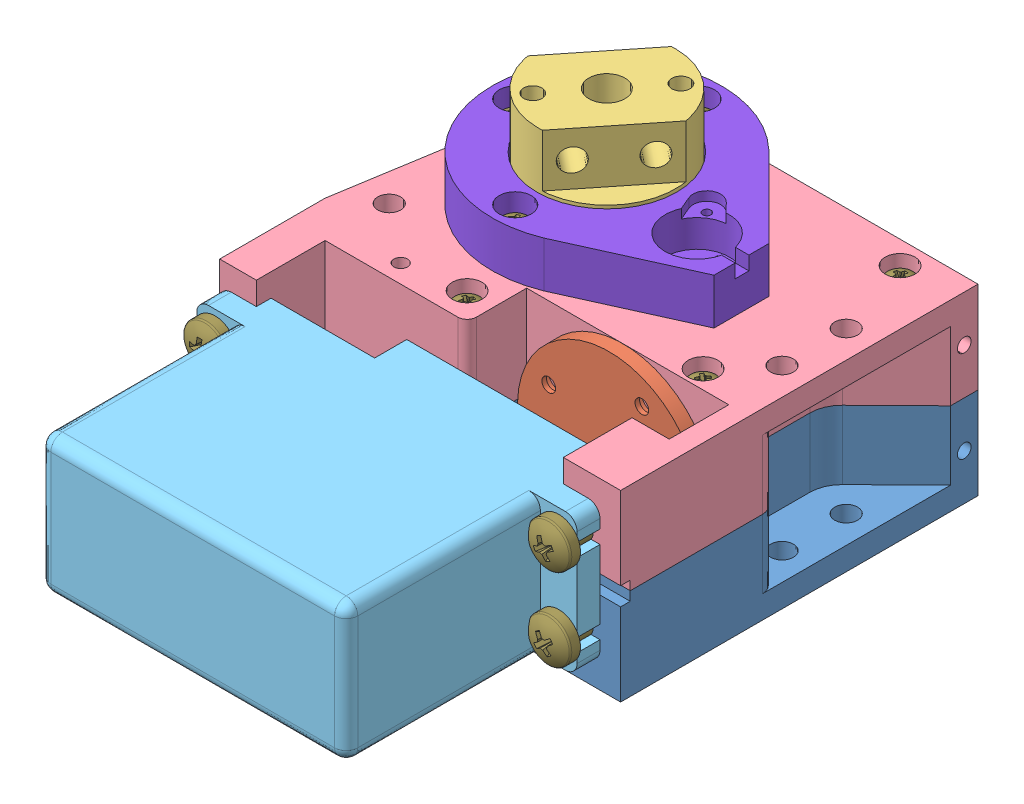
SolidWorks assembly Mirrorgearbox1, configuration Default. Lengths in mm.
Overall size (90.22 74 134.56).
28 component instances, 12 part files, 58 mates.
Components (placement in the parent):
- Mirrorservo gearbox-1: Mirrorservo gearbox [Default] at (7.4002 -24.2748 -89.7718) x (1 0 0) z (0 -1 0) size (87.5 78 20)
- wormscrew-1: wormscrew [Default] at (21.4002 -4.2748 -75.7718) x (-0.47589 -0.879505 0) z (0 0 -1) size (40 40 51)
- driveshaft cog-1: driveshaft cog [Default] at (-6.5998 -9.2748 -103.2718) x (0.623441 0 -0.78187) z (0 1 0) size (49.29 49.31 47)
- Mirrorgearbox top-1: Mirrorgearbox top [Default] at (-6.5998 15.7252 -103.2718) x (-1 0 0) z (0 1 0) size (87.5 78 40)
- HS-805BB-1: HS-805BB [Default] at (2.9002 -19.2748 -28.6693) x (1 0 0) z (0 1 0) size (83 68.8 30)
- 608ZZ-1: 608ZZ [Default] at (21.4002 -4.2748 -127.5718) x (0.996867 0.079098 0) z (0 0 1) size (22 22 7)
- 6806 30x42x7-1: 6806 30x42x7 [Default] at (-6.5998 -22.2748 -103.2718) x (0.979879 0 -0.199591) z (0 1 0) size (42 42 7)
- 6806 30x42x7-2: 6806 30x42x7 [Default] at (-6.5998 9.7252 -103.2718) x (0.968497 0 -0.249026) z (0 -1 0) size (42 42 7)
- Mirrorbottom plate pot holder-1: Mirrorbottom plate pot holder [Default] at (-6.5998 15.7252 -103.2718) x (0 0 1) z (0 -1 0) size (50 60 10)
- cog brace-1: cog brace [Default] at (18.6002 9.7252 -104.6718) x (1 0 0) z (0 -1 0) size (8.5 22.65 3)
- pot cog-1: pot cog [Default] at (18.6002 12.7252 -97.7718) x (0.51355 0 -0.85806) z (0 -1 0) size (28 27.88 7.9)
- driveshaft-1: driveshaft [Default] at (-6.5998 -9.2748 -103.2718) x (-0.623441 0 0.78187) z (0 -1 0) size (36.44 35.48 27)
- Pan Head Cross Recess Screw_ISO-1: Pan Head Cross Recess Screw_ISO [ISO 7045 - M3 x 10 - Z --- 10N] at (-26.5998 23.1252 -103.2718) x (0 -1 0) z (0 0 -1) size (12.35 5.6 5.6)
- Pan Head Cross Recess Screw_ISO-2: Pan Head Cross Recess Screw_ISO [ISO 7045 - M3 x 10 - Z --- 10N] at (-6.5998 23.1252 -123.2718) x (0 -1 0) z (0.495758 0 -0.868461) size (12.35 5.6 5.6)
- Pan Head Cross Recess Screw_ISO-3: Pan Head Cross Recess Screw_ISO [ISO 7045 - M3 x 10 - Z --- 10N] at (-6.5998 23.1252 -83.2718) x (0 -1 0) z (0.927545 0 -0.373711) size (12.35 5.6 5.6)
- Pan Head Cross Recess Screw_ISO-4: Pan Head Cross Recess Screw_ISO [ISO 7045 - M5 x 12 - Z --- 12N] at (-34.5998 -13.2748 -42.0718) x (0 0 -1) z (-1 0 0) size (15.63 9.5 9.5)
- Pan Head Cross Recess Screw_ISO-5: Pan Head Cross Recess Screw_ISO [ISO 7045 - M5 x 12 - Z --- 12N] at (-34.5998 4.7252 -42.0718) x (0 0 -1) z (-1 0 0) size (15.63 9.5 9.5)
- Pan Head Cross Recess Screw_ISO-6: Pan Head Cross Recess Screw_ISO [ISO 7045 - M3 x 30 - Z --- 25N] at (-27.0895 14.1252 -123.7718) x (0 -1 0) z (0 0 -1) size (32.35 5.6 5.6)
- Pan Head Cross Recess Screw_ISO-7: Pan Head Cross Recess Screw_ISO [ISO 7045 - M3 x 30 - Z --- 25N] at (-18.0998 -22.6748 -69.7718) x (0 1 0) z (0 0 -1) size (32.35 5.6 5.6)
- Pan Head Cross Recess Screw_ISO-8: Pan Head Cross Recess Screw_ISO [ISO 7045 - M3 x 30 - Z --- 25N] at (34.9002 14.1252 -82.7718) x (0 -1 0) z (-0.8218 0 -0.569776) size (32.35 5.6 5.6)
- Pan Head Cross Recess Screw_ISO-9: Pan Head Cross Recess Screw_ISO [ISO 7045 - M3 x 30 - Z --- 25N] at (-5.5998 14.1252 -71.7718) x (0 -1 0) z (0.38373 0 -0.923445) size (32.35 5.6 5.6)
- Pan Head Cross Recess Screw_ISO-10: Pan Head Cross Recess Screw_ISO [ISO 7045 - M2 x 6 - Z --- 6N] at (18.6002 6.6252 -115.2718) x (0 1 0) z (0.855583 0 0.517665) size (7.57 4 4)
- Pan Head Cross Recess Screw_ISO-11: Pan Head Cross Recess Screw_ISO [ISO 7045 - M3 x 5 - Z --- 5N] at (-19.8916 -13.6748 -113.8703) x (0 1 0) z (0.934817 0 -0.355129) size (7.35 5.6 5.6)
- Pan Head Cross Recess Screw_ISO-12: Pan Head Cross Recess Screw_ISO [ISO 7045 - M3 x 5 - Z --- 5N] at (9.2246 -13.6748 -109.4836) x (0 1 0) z (-0.000145 0 -1) size (7.35 5.6 5.6)
- Pan Head Cross Recess Screw_ISO-13: Pan Head Cross Recess Screw_ISO [ISO 7045 - M3 x 5 - Z --- 5N] at (-9.1325 -13.6748 -86.4615) x (0 1 0) z (-0.12044 0 -0.992721) size (7.35 5.6 5.6)
- Pan Head Cross Recess Screw_ISO-14: Pan Head Cross Recess Screw_ISO [ISO 7045 - M3 x 30 - Z --- 25N] at (36.9002 14.1252 -123.7718) x (0 -1 0) z (0.993717 0 0.111922) size (32.35 5.6 5.6)
- Pan Head Cross Recess Screw_ISO-15: Pan Head Cross Recess Screw_ISO [ISO 7045 - M5 x 12 - Z --- 12N] at (40.4002 4.7252 -42.0718) x (0 0 -1) z (0.445798 -0.895134 0) size (15.63 9.5 9.5)
- Pan Head Cross Recess Screw_ISO-16: Pan Head Cross Recess Screw_ISO [ISO 7045 - M5 x 12 - Z --- 12N] at (40.4002 -13.2748 -42.0718) x (0 0 -1) z (0.583619 -0.812027 0) size (15.63 9.5 9.5)
Mates (geometry in assembly coordinates):
- Coincident1: coincident anti-aligned: plane of Mirrorservo gearbox-1 through (-34.0998 -4.2748 -50.7718) normal (0 0 1); plane of HS-805BB-1 through (-38.5998 10.7252 -50.7718) normal (0 0 -1)
- Concentric1: concentric aligned: circle of wormscrew-1; circle of HS-805BB-1
- Coincident2: coincident anti-aligned: plane of Mirrorservo gearbox-1 through (36.4002 11.2494 -65.7718) normal (-1 0 0); plane of HS-805BB-1 through (36.4002 10.7252 -50.7718) normal (1 0 0)
- Coincident3: coincident anti-aligned: plane of Mirrorservo gearbox-1 through (32.6502 -15.4748 -127.5718) normal (0 0 1); plane of 608ZZ-1 through (21.4002 -4.2748 -127.5718) normal (0 0 -1)
- Coincident4: coincident anti-aligned: plane of Mirrorservo gearbox-1 through (-6.5998 -22.2748 -103.2718) normal (0 1 0); plane of 6806 30x42x7-1 through (-6.5998 -22.2748 -103.2718) normal (0 -1 0)
- Concentric2: concentric anti-aligned: cylinder of Mirrorservo gearbox-1; cylinder of 6806 30x42x7-1
- Coincident5: coincident anti-aligned: plane of driveshaft cog-1 through (-6.5998 2.7252 -103.2718) normal (0 1 0); plane of 6806 30x42x7-2 through (-6.5998 2.7252 -103.2718) normal (0 -1 0)
- Concentric4: concentric anti-aligned: cylinder of HS-805BB-1; cylinder of Pan Head Cross Recess Screw_ISO-15
- Coincident6: coincident anti-aligned: plane of HS-805BB-1 through (36.4002 10.7252 -45.7718) normal (0 0 1); plane of Pan Head Cross Recess Screw_ISO-15 through (42.638 5.8397 -45.7718) normal (0 0 -1)
- Concentric5: concentric anti-aligned: cylinder of HS-805BB-1; cylinder of Pan Head Cross Recess Screw_ISO-16
- Coincident7: coincident anti-aligned: plane of HS-805BB-1 through (36.4002 10.7252 -45.7718) normal (0 0 1); plane of Pan Head Cross Recess Screw_ISO-16 through (42.4302 -11.8157 -45.7718) normal (0 0 -1)
- Concentric6: concentric anti-aligned: cylinder of HS-805BB-1; cylinder of Pan Head Cross Recess Screw_ISO-4
- Coincident8: coincident anti-aligned: plane of HS-805BB-1 through (-30.5998 10.7252 -45.7718) normal (0 0 1); plane of Pan Head Cross Recess Screw_ISO-4 through (-34.5998 -15.7748 -45.7718) normal (0 0 -1)
- Concentric7: concentric anti-aligned: cylinder of HS-805BB-1; cylinder of Pan Head Cross Recess Screw_ISO-5
- Coincident9: coincident anti-aligned: plane of HS-805BB-1 through (-30.5998 10.7252 -45.7718) normal (0 0 1); plane of Pan Head Cross Recess Screw_ISO-5 through (-34.5998 2.2252 -45.7718) normal (0 0 -1)
- Coincident10: coincident anti-aligned: plane of Mirrorservo gearbox-1 through (-18.0998 -20.2748 -69.7718) normal (0 -1 0); plane of Pan Head Cross Recess Screw_ISO-7 through (-16.5998 -20.2748 -69.7718) normal (0 1 0)
- Coincident11: coincident anti-aligned: plane of cog brace-1 through (23.1002 8.2252 -111.6718) normal (0 -1 0); plane of Pan Head Cross Recess Screw_ISO-10 through (18.0825 8.2252 -114.4162) normal (0 1 0)
- Concentric8: concentric aligned: cylinder of driveshaft cog-1; cylinder of Pan Head Cross Recess Screw_ISO-11
- Concentric9: concentric anti-aligned: cylinder of Mirrorbottom plate pot holder-1; cylinder of Pan Head Cross Recess Screw_ISO-2
- Coincident12: coincident anti-aligned: plane of Mirrorbottom plate pot holder-1 through (-6.5998 20.7252 -123.2718) normal (0 1 0); plane of Pan Head Cross Recess Screw_ISO-2 through (-7.9025 20.7252 -124.0154) normal (0 -1 0)
- Concentric10: concentric anti-aligned: cylinder of Mirrorbottom plate pot holder-1; cylinder of Pan Head Cross Recess Screw_ISO-3
- Coincident13: coincident anti-aligned: plane of Mirrorbottom plate pot holder-1 through (-6.5998 20.7252 -83.2718) normal (0 1 0); plane of Pan Head Cross Recess Screw_ISO-3 through (-7.1604 20.7252 -84.6631) normal (0 -1 0)
- Coincident14: coincident anti-aligned: plane of Mirrorbottom plate pot holder-1 through (-26.5998 20.7252 -103.2718) normal (0 1 0); plane of Pan Head Cross Recess Screw_ISO-1 through (-28.0998 20.7252 -103.2718) normal (0 -1 0)
- Concentric11: concentric anti-aligned: cylinder of Mirrorbottom plate pot holder-1; cylinder of Pan Head Cross Recess Screw_ISO-1
- GearMate1: gear = 0.001 : 0.013: circle of driveshaft cog-1; circle of wormscrew-1
- GearMate2: gear = 0.001 : 0.001: circle of pot cog-1; circle of driveshaft cog-1
- Coincident16: coincident aligned: plane of Mirrorgearbox top-1 through (-6.5998 9.7252 -103.2718) normal (0 -1 0); circle of 6806 30x42x7-2
- Concentric13: concentric anti-aligned: cylinder of Mirrorgearbox top-1; cylinder of 6806 30x42x7-2
- Concentric14: concentric anti-aligned: cylinder of driveshaft cog-1; cylinder of Mirrorgearbox top-1
- Coincident17: coincident anti-aligned: plane of Mirrorgearbox top-1 through (18.6002 12.7252 -97.7718) normal (0 -1 0); plane of pot cog-1 through (20.5571 12.7252 -91.7908) normal (0 1 0)
- Concentric16: concentric aligned: circle of cog brace-1; cylinder of Pan Head Cross Recess Screw_ISO-10
- Concentric17: concentric aligned: cylinder of Mirrorgearbox top-1; cylinder of Pan Head Cross Recess Screw_ISO-10
- Coincident19: coincident anti-aligned: plane of Mirrorgearbox top-1 through (23.1002 9.7252 -108.9666) normal (0 -1 0); plane of cog brace-1 through (20.8502 9.7252 -97.6718) normal (0 1 0)
- Concentric19: concentric anti-aligned: circle of driveshaft cog-1; circle of driveshaft-1
- Coincident22: coincident aligned: cylinder of driveshaft cog-1; circle of driveshaft-1
- Coincident23: coincident anti-aligned: plane of Pan Head Cross Recess Screw_ISO-11 through (-19.3589 -11.2748 -112.4681) normal (0 1 0); plane of driveshaft-1 through (-19.8916 -11.2748 -113.8703) normal (0 -1 0)
- Coincident24: coincident anti-aligned: plane of driveshaft cog-1 through (-6.5998 -9.2748 -103.2718) normal (0 -1 0); plane of driveshaft-1 through (-6.5998 -9.2748 -103.2718) normal (0 1 0)
- Coincident25: coincident aligned: circle of driveshaft-1; cylinder of Pan Head Cross Recess Screw_ISO-12
- Coincident26: coincident aligned: plane of driveshaft-1 through (9.2246 -11.2748 -109.4836) normal (0 -1 0); circle of Pan Head Cross Recess Screw_ISO-12
- Coincident27: coincident aligned: circle of driveshaft-1; cylinder of Pan Head Cross Recess Screw_ISO-13
- Coincident28: coincident aligned: plane of driveshaft-1 through (-9.1325 -11.2748 -86.4615) normal (0 -1 0); circle of Pan Head Cross Recess Screw_ISO-13
- Concentric23: concentric aligned: circle of Mirrorgearbox top-1; cylinder of 608ZZ-1
- Coincident29: coincident anti-aligned: plane of Mirrorgearbox top-1 through (32.6502 7.2252 -127.5718) normal (0 0 1); plane of 608ZZ-1 through (21.4002 -4.2748 -127.5718) normal (0 0 -1)
- Concentric24: concentric anti-aligned: cylinder of wormscrew-1; cylinder of Mirrorgearbox top-1
- Coincident31: coincident anti-aligned: plane of wormscrew-1 through (21.4002 -4.2748 -78.7718) normal (0 0 -1); plane of Mirrorgearbox top-1 through (0.4002 -4.2748 -78.7718) normal (0 0 1)
- Coincident32: coincident anti-aligned: circle of Mirrorservo gearbox-1; cylinder of Pan Head Cross Recess Screw_ISO-6
- Concentric25: concentric aligned: cylinder of Mirrorgearbox top-1; cylinder of Pan Head Cross Recess Screw_ISO-6
- Coincident33: coincident anti-aligned: plane of Mirrorgearbox top-1 through (-28.7895 11.7252 -123.7718) normal (0 1 0); plane of Pan Head Cross Recess Screw_ISO-6 through (-28.5895 11.7252 -123.7718) normal (0 -1 0)
- Coincident34: coincident anti-aligned: plane of Mirrorservo gearbox-1 through (-34.0998 -4.2748 -128.7718) normal (0 1 0); plane of Mirrorgearbox top-1 through (-1.5998 -4.2748 -67.7718) normal (0 -1 0)
- Concentric26: concentric anti-aligned: circle of Mirrorgearbox top-1; circle of Pan Head Cross Recess Screw_ISO-9
- Coincident35: coincident aligned: plane of Mirrorgearbox top-1 through (-7.2998 11.7252 -71.7718) normal (0 1 0); circle of Pan Head Cross Recess Screw_ISO-9
- Concentric27: concentric anti-aligned: circle of Mirrorgearbox top-1; cylinder of Pan Head Cross Recess Screw_ISO-8
- Coincident36: coincident aligned: plane of Mirrorgearbox top-1 through (33.2002 11.7252 -82.7718) normal (0 1 0); circle of Pan Head Cross Recess Screw_ISO-8
- Concentric28: concentric anti-aligned: circle of Mirrorgearbox top-1; circle of Pan Head Cross Recess Screw_ISO-14
- Coincident37: coincident anti-aligned: plane of Mirrorgearbox top-1 through (35.2002 11.7252 -123.7718) normal (0 1 0); plane of Pan Head Cross Recess Screw_ISO-14 through (37.068 11.7252 -125.2624) normal (0 -1 0)
- Concentric29: concentric anti-aligned: cylinder of driveshaft cog-1; cylinder of Mirrorbottom plate pot holder-1
- Coincident38: coincident anti-aligned: plane of Mirrorgearbox top-1 through (-1.5998 15.7252 -67.7718) normal (0 1 0); plane of Mirrorbottom plate pot holder-1 through (-6.5998 15.7252 -103.2718) normal (0 -1 0)
- Concentric30: concentric anti-aligned: cylinder of Mirrorgearbox top-1; circle of Mirrorbottom plate pot holder-1
